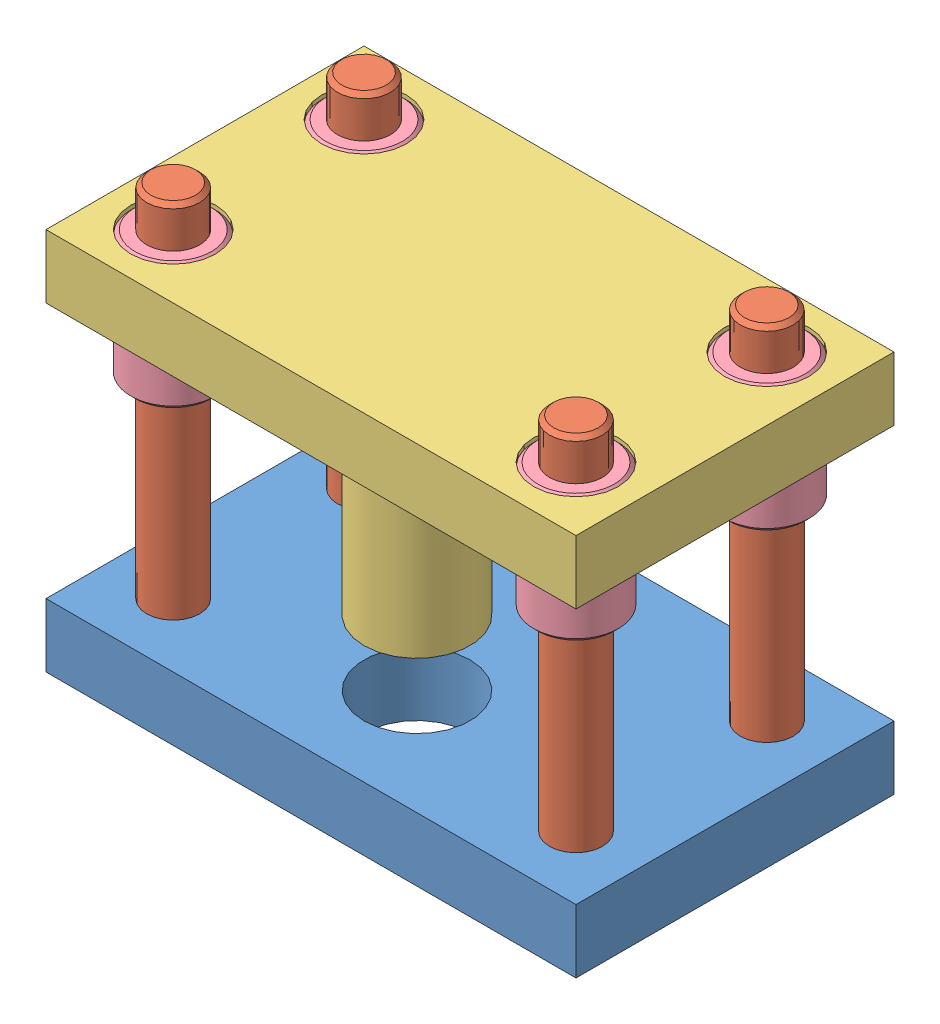
SolidWorks assembly Assem1, configuration Default. Lengths in mm.
Overall size (6350 5080 3810).
10 component instances, 4 part files, 18 mates.
Components (placement in the parent):
- bottom plate-1: bottom plate [Default] at (2625.7042 1749.7324 5543.1302) size (6350 762 3810)
- guide pillar-1: guide pillar [Default] at (212.7042 1749.7324 6686.1302) size (635 5080 635)
- guide pillar-2: guide pillar [Default] at (5038.7042 1749.7324 6686.1302) size (635 5080 635)
- guide pillar-3: guide pillar [Default] at (212.7042 1749.7324 4400.1302) x (0.995389 0 0.095923) z (-0.095923 0 0.995389) size (635 5080 635)
- guide pillar-4: guide pillar [Default] at (5038.7042 1749.7324 4400.1302) x (0.969078 0 -0.246754) z (0.246754 0 0.969078) size (635 5080 635)
- top plate-1: top plate [Default] at (2625.7042 5578.5052 5543.1302) size (6350 3048 3810)
- guide bush-1: guide bush [Default] at (212.7042 4816.5052 6686.1302) x (0.318138 0 0.948044) z (-0.948044 0 0.318138) size (1016 1524 1016)
- guide bush-2: guide bush [Default] at (212.7042 4816.5052 4400.1302) x (0.569784 0 0.821795) z (-0.821795 0 0.569784) size (1016 1524 1016)
- guide bush-3: guide bush [Default] at (5038.7042 4816.5052 4400.1302) x (0.519498 0 0.854472) z (-0.854472 0 0.519498) size (1016 1524 1016)
- guide bush-4: guide bush [Default] at (5038.7042 4816.5052 6686.1302) x (0.505038 0 -0.863097) z (0.863097 0 0.505038) size (1016 1524 1016)
Mates (geometry in assembly coordinates):
- Concentric1: concentric aligned: cylinder of bottom plate-1 through (212.7042 2511.7324 6686.1302) axis (0 -1 0) radius 317.5; cylinder of guide pillar-1 through (212.7042 6829.7324 6686.1302) axis (0 -1 0) radius 317.5
- Concentric2: concentric aligned: cylinder of bottom plate-1 through (5038.7042 2511.7324 6686.1302) axis (0 -1 0) radius 317.5; cylinder of guide pillar-2 through (5038.7042 6829.7324 6686.1302) axis (0 -1 0) radius 317.5
- Coincident1: coincident anti-aligned: circle of bottom plate-1; cylinder of guide pillar-4 through (5038.7042 6829.7324 4400.1302) axis (0 -1 0) radius 317.5
- Coincident2: coincident anti-aligned: circle of bottom plate-1; cylinder of guide pillar-3 through (212.7042 6829.7324 4400.1302) axis (0 -1 0) radius 317.5
- Coincident3: coincident aligned: plane of bottom plate-1 through (2625.7042 1749.7324 5543.1302) normal (0 -1 0); plane of guide pillar-1 through (212.7042 1749.7324 6686.1302) normal (0 -1 0)
- Coincident4: coincident aligned: plane of bottom plate-1 through (2625.7042 1749.7324 5543.1302) normal (0 -1 0); plane of guide pillar-2 through (5038.7042 1749.7324 6686.1302) normal (0 -1 0)
- Coincident5: coincident aligned: plane of bottom plate-1 through (2625.7042 1749.7324 5543.1302) normal (0 -1 0); plane of guide pillar-3 through (212.7042 1749.7324 4400.1302) normal (0 -1 0)
- Coincident6: coincident aligned: plane of bottom plate-1 through (2625.7042 1749.7324 5543.1302) normal (0 -1 0); plane of guide pillar-4 through (5038.7042 1749.7324 4400.1302) normal (0 -1 0)
- Concentric3: concentric aligned: cylinder of guide pillar-1 through (212.7042 6829.7324 6686.1302) axis (0 -1 0) radius 317.5; cylinder of top plate-1 through (212.7042 6340.5052 6686.1302) axis (0 -1 0) radius 508
- Concentric4: concentric anti-aligned: cylinder of guide pillar-2 through (5038.7042 6829.7324 6686.1302) axis (0 -1 0) radius 317.5; circle of top plate-1
- Concentric5: concentric anti-aligned: circle of top plate-1; cylinder of guide bush-1 through (212.7042 6340.5052 6686.1302) axis (0 -1 0) radius 508
- Coincident7: coincident anti-aligned: circle of top plate-1; cylinder of guide bush-2 through (212.7042 6340.5052 4400.1302) axis (0 -1 0) radius 508
- Coincident8: coincident anti-aligned: circle of top plate-1; cylinder of guide bush-3 through (5038.7042 6340.5052 4400.1302) axis (0 -1 0) radius 508
- Coincident9: coincident anti-aligned: circle of top plate-1; cylinder of guide bush-4 through (5038.7042 6340.5052 6686.1302) axis (0 -1 0) radius 508
- Coincident10: coincident aligned: plane of top plate-1 through (2625.7042 6340.5052 5543.1302) normal (0 1 0); circle of guide bush-1
- Coincident12: coincident aligned: plane of top plate-1 through (2625.7042 6340.5052 5543.1302) normal (0 1 0); plane of guide bush-2 through (212.7042 6340.5052 4400.1302) normal (0 1 0)
- Coincident13: coincident aligned: plane of top plate-1 through (2625.7042 6340.5052 5543.1302) normal (0 1 0); plane of guide bush-3 through (5038.7042 6340.5052 4400.1302) normal (0 1 0)
- Coincident14: coincident aligned: plane of top plate-1 through (2625.7042 6340.5052 5543.1302) normal (0 1 0); plane of guide bush-4 through (5038.7042 6340.5052 6686.1302) normal (0 1 0)
